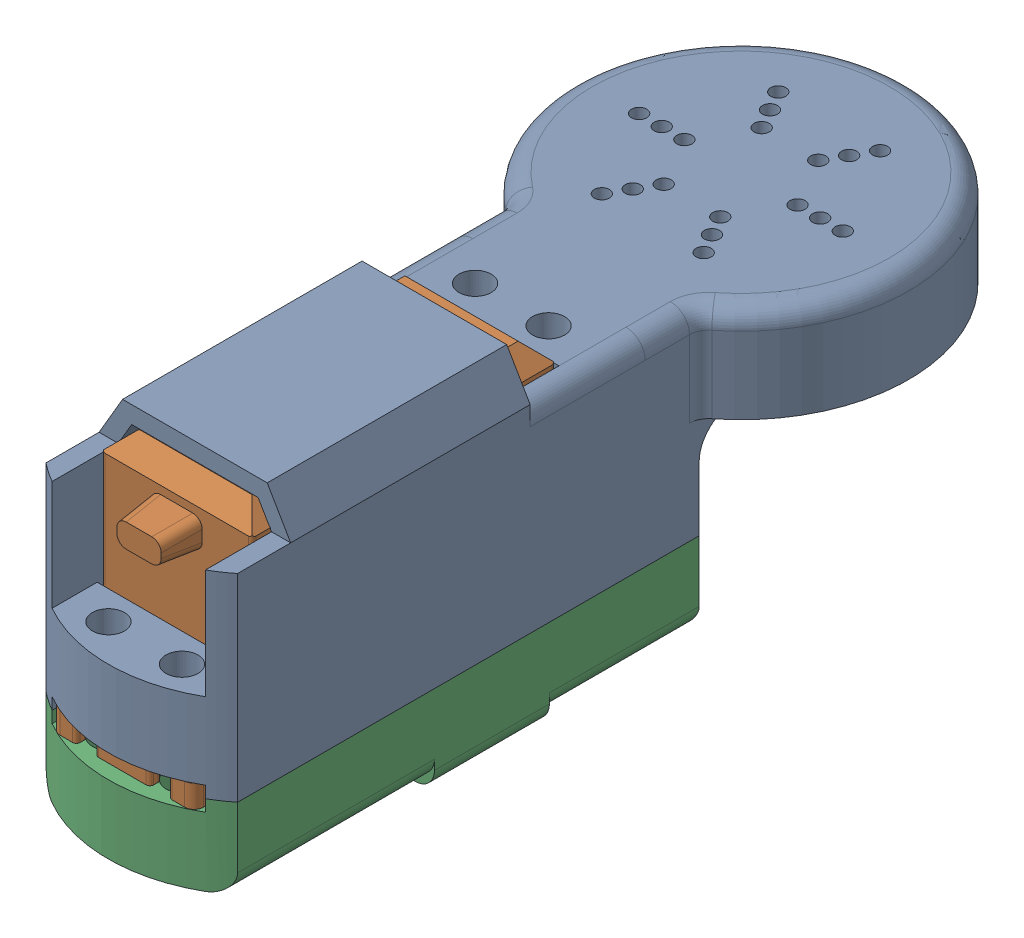
SolidWorks assembly Link2Assem, configuration Default. Lengths in mm.
Overall size (44.45 48.15 106.1).
3 component instances, 3 part files, 7 mates.
Components (placement in the parent):
- Link2Connect-1: Link2Connect [Default] at origin size (44.45 31.6 106.1)
- MG995_Servo-1: MG995_Servo [Default] at (0 15.5888 54.675) x (0 0 -1) z (-1 0 0) size (54.65 45.7 20.01)
- Link2SecondHalf-1: Link2SecondHalf [Default] at (0 -13.5611 63.5) size (25.4 11.92 65.83)
Mates (geometry in assembly coordinates):
- Parallel1: parallel anti-aligned: plane of MG995_Servo-1 through (10 -12.0612 34.55) normal (0 0 -1); plane of Link2Connect-1 through (-10.16 -46.0731 34.29) normal (0 0 1)
- Width1: width aligned: plane of MG995_Servo-1 through (-10 -12.0612 74.8) normal (-1 0 0); plane of Link2Connect-1 through (10 -12.0612 74.8) normal (1 0 0); plane of MG995_Servo-1 through (12.7 -6.35 25.4) normal (1 0 0); plane of Link2Connect-1 through (-12.7 -6.35 18.239) normal (-1 0 0)
- Distance2: distance = 1.4999 mm anti-aligned: plane of Link2Connect-1 through (0 -13.5611 0) normal (0 -1 0); plane of MG995_Servo-1 through (0 -12.0612 54.675) normal (0 1 0)
- Distance5: distance = 63.5 mm: line of Link2Connect-1 through (0 27.5459 0) axis (0 -1 0); point of MG995_Servo-1
- Coincident5: coincident anti-aligned: plane of Link2Connect-1 through (0 -13.5611 0) normal (0 -1 0); plane of Link2SecondHalf-1 through (0 -13.5611 0) normal (0 1 0)
- Coincident6: coincident aligned: plane of Link2Connect-1 through (12.7 -6.35 25.4) normal (1 0 0); plane of Link2SecondHalf-1 through (12.7 -24.2113 18.239) normal (1 0 0)
- Concentric2: concentric anti-aligned: cylinder of Link2Connect-1 through (0 -1.8517 63.5) axis (0 -1 0) radius 20.3708; cylinder of Link2SecondHalf-1 through (0 -24.2113 63.5) axis (0 1 0) radius 20.3708
